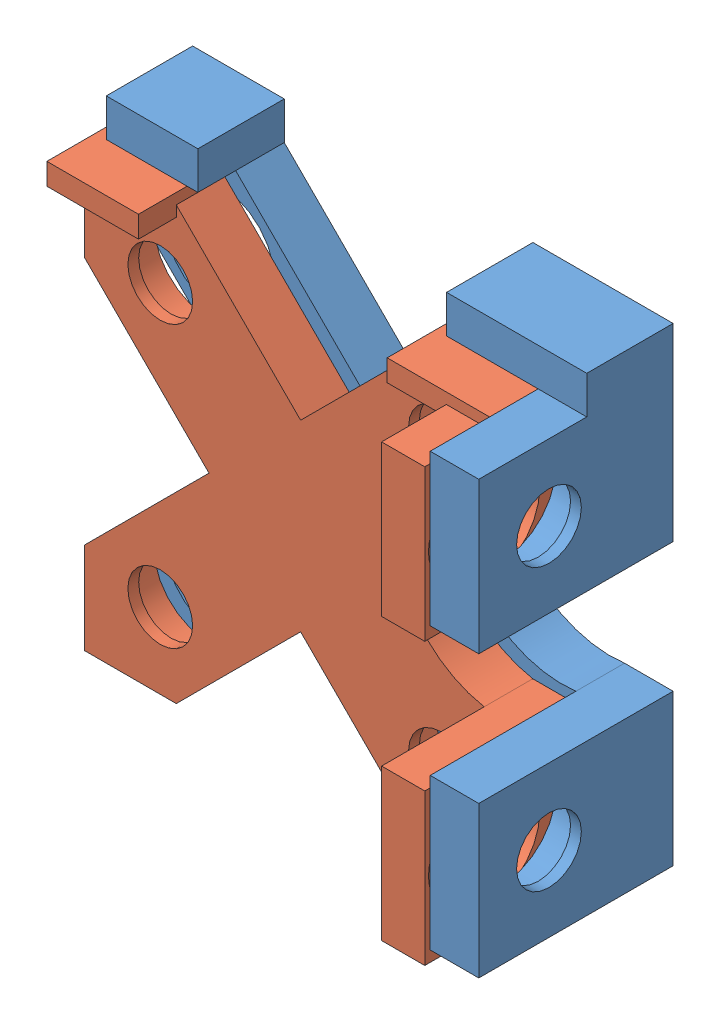
SolidWorks assembly Montagem1, configuration Valor predeterminado. Lengths in mm.
Overall size (45.5 44.5 18.5).
2 component instances, 2 part files, 3 mates.
Components (placement in the parent):
- base-1: base [Valor predeterminado] at (-8.8517 0.656 35.5) size (44.5 43.5 18)
- ferramenta-1: ferramenta [Valor predeterminado] at (-9.8517 -0.344 40) size (41 41 14)
Mates (geometry in assembly coordinates):
- Coincidente1: coincident anti-aligned: plane of base-1 through (-8.8517 0.656 40) normal (0 0 1); plane of ferramenta-1 through (-9.8517 -0.344 40) normal (0 0 -1)
- Coincidente2: coincident anti-aligned: plane of base-1 through (-8.8517 20.656 35.5) normal (0 -1 0); plane of ferramenta-1 through (-9.8517 20.656 40) normal (0 1 0)
- Coincidente3: coincident anti-aligned: plane of base-1 through (11.1483 0.656 35.5) normal (-1 0 0); plane of ferramenta-1 through (11.1483 -0.344 40) normal (1 0 0)
